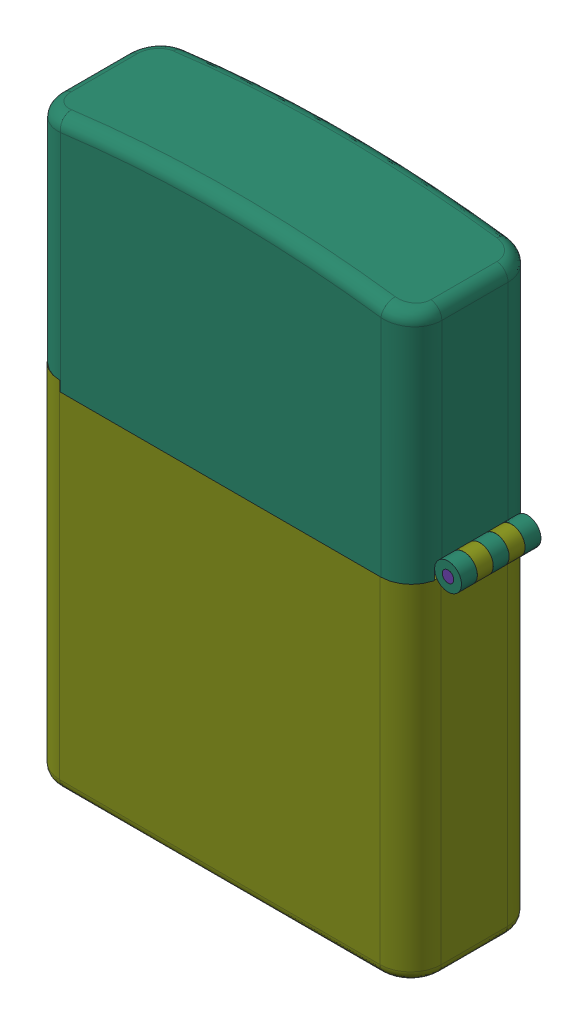
SolidWorks assembly ZLASSEMBLY, configuration Default. Lengths in mm.
Overall size (44.09 59.33 43.46).
18 component instances, 17 part files, 26 mates.
Components (placement in the parent):
- ZLSAP-101 INNER BODY  final-1: ZLSAP-101 INNER BODY  final [Default] at (-7.9372 -6.5366 -12.4236) size (36.03 50.8 10.92)
- ZLSAP- 103 FLINT WHEEL RIVET-1: ZLSAP- 103 FLINT WHEEL RIVET [Default] at (-2.0952 35.9322 -20.3738) x (0.999904 -0.013836 0) z (0 0 1) size (3.05 3.05 5.61)
- ZLSAP-102 FLINT WHEEL-1: ZLSAP-102 FLINT WHEEL [Default] at (-2.0952 35.9322 -19.6118) x (0.056047 -0.998428 0) z (0 0 1) size (10.96 10.96 3.56)
- ZLSAP-104 CAM SPRING-2: ZLSAP-104 CAM SPRING [Default] at (6.0886 28.617 -17.8658) x (0.999917 0 0.012886) z (0.012886 0 -0.999917) size (18.35 4.12 6.22)
- ZLSAP-108 EYELET-1: ZLSAP-108 EYELET [Default] at (9.5562 26.2294 -17.8846) x (-0.386007 0 0.922496) z (0 1 0) size (4.57 4.57 2.79)
- ZLSAP-107 WICK-1: ZLSAP-107 WICK [Default] at (9.5562 32.8921 -17.8846) x (-0.99856 0 0.053653) z (0 -1 0) size (1.28 1.29 20.32)
- ZLSAP-105 CAM-1: ZLSAP-105 CAM [Default] at (23.9735 39.612 -16.7416) x (-0.956559 -0.291538 0) z (0 0 -1) size (10.34 13.18 2.54)
- ZLSAP-106 CAM RIVET PIN-1: ZLSAP-106 CAM RIVET PIN [Default] at (23.7253 34.2136 -20.6278) x (-0.237452 -0.971399 0) z (0 0 1) size (2.79 2.79 5.87)
- SA2-1: SA2 [Default] at (2.1781 20.7012 -47.3424) x (0.77642 0 -0.630216) z (0 1 0) size (32.9 29.26 133.24)
  - ZLSAP-205 SPRING-2: ZLSAP-205 SPRING [COMPRESSED] at (-23.8276 -18.5998 -22.0561) size (3.08 2.67 25.15)
  - ZLSAP-206 SCREW-2: ZLSAP-206 SCREW [Default] at (-23.8276 -18.5998 -29.3713) x (-0.090818 0.995868 0) z (0 0 -1) size (6.35 6.35 9.65)
  - ZLSAP-204 SPRING TIP-2: ZLSAP-204 SPRING TIP [Default] at (-23.8815 -18.7291 7.1666) x (-0.123666 -0.992324 0) z (0.992324 -0.123666 0) size (2.34 7.24 2.34)
  - ZLSAP-203 FLINT-2: ZLSAP-203 FLINT [Default] at (-23.8815 -18.7291 7.1666) x (-0.578855 0.81543 0) z (0 0 1) size (2.29 2.29 2.96)
  - ZLSAP-202 FELT PAD-2: ZLSAP-202 FELT PAD [Default] at (3.6679 -34.702 -27.7965) x (-0.77642 0.630216 0) z (0.630216 0.77642 0) size (34.54 5.27 9.65)
  - ZLSAP-201 TUBE-2: ZLSAP-201 TUBE [Default] at (-23.8276 -18.5998 7.7635) size (4.83 5 35.56)
- ZLSAP-301 LID-2: ZLSAP-301 LID [Default] at (28.9173 24.807 -11.5283) x (-1 0 0) z (0 0 -1) size (40.72 25.09 12.7)
- ZLSAP-302 BODY CASE-2: ZLSAP-302 BODY CASE [Default] at (28.842 -9.7624 -17.8846) x (-1 0 0) z (0 0 -1) size (40.79 36.93 12.7)
- ZLSAP-303 CASE HINGE PIN-2: ZLSAP-303 CASE HINGE PIN [Default] at (30.1882 25.823 -21.8661) x (-0.339081 0.940757 0) z (0 0 1) size (1.14 1.14 7.95)
Mates (geometry in assembly coordinates):
- Concentric8: concentric anti-aligned: circle of ZLSAP-101 INNER BODY  final-1; circle of ZLSAP-104 CAM SPRING-2
- Concentric9: concentric anti-aligned: circle of ZLSAP-101 INNER BODY  final-1; circle of ZLSAP-104 CAM SPRING-2
- Coincident7: coincident anti-aligned: plane of ZLSAP-101 INNER BODY  final-1 through (23.3397 28.4646 -17.8846) normal (0 1 0); plane of ZLSAP-104 CAM SPRING-2 through (6.1287 28.4646 -20.977) normal (0 -1 0)
- Concentric10: concentric anti-aligned: circle of ZLSAP-104 CAM SPRING-2; circle of ZLSAP-108 EYELET-1
- Coincident9: coincident anti-aligned: plane of ZLSAP-104 CAM SPRING-2 through (6.1287 28.7694 -20.977) normal (0 1 0); plane of ZLSAP-108 EYELET-1 through (9.5562 28.7694 -17.8846) normal (0 -1 0)
- Concentric11: concentric aligned: cylinder of ZLSAP-108 EYELET-1 through (9.5562 29.0234 -17.8846) axis (0 -1 0) radius 1.2446; circle of ZLSAP-107 WICK-1
- Concentric14: concentric anti-aligned: cylinder of ZLSAP-101 INNER BODY  final-1 through (-2.0952 35.9322 -25.5808) axis (0 0 1) radius 1.4732; cylinder of ZLSAP- 103 FLINT WHEEL RIVET-1 through (-2.0952 35.9322 -15.4208) axis (0 0 -1) radius 1.0795
- Coincident12: coincident anti-aligned: plane of ZLSAP-101 INNER BODY  final-1 through (-7.9372 44.2634 -15.4208) normal (0 0 1); plane of ZLSAP- 103 FLINT WHEEL RIVET-1 through (-2.0952 35.9322 -15.4208) normal (0 0 -1)
- Width1: width anti-aligned: plane of ZLSAP-105 CAM-1 through (27.0462 40.3092 -16.7416) normal (0 0 1); plane of ZLSAP-105 CAM-1 through (27.0462 40.3092 -19.2816) normal (0 0 -1); plane of ZLSAP-106 CAM RIVET PIN-1 through (23.7253 34.2136 -20.6786) normal (0 0 -1); plane of ZLSAP-106 CAM RIVET PIN-1 through (23.7253 34.2136 -15.3446) normal (0 0 -1)
- Concentric21: concentric aligned: cylinder of ZLSAP-105 CAM-1 through (23.7253 34.2136 -19.2816) axis (0 0 -1) radius 0.9652; cylinder of ZLSAP-106 CAM RIVET PIN-1 through (23.7253 34.2136 -15.3446) axis (0 0 -1) radius 0.9652
- Concentric22: concentric anti-aligned: cylinder of ZLSAP-101 INNER BODY  final-1 through (23.7253 34.2136 -23.3456) axis (0 0 1) radius 0.9779; cylinder of ZLSAP-106 CAM RIVET PIN-1 through (23.7253 34.2136 -15.3446) axis (0 0 -1) radius 0.9652
- Coincident17: coincident anti-aligned: plane of ZLSAP-101 INNER BODY  final-1 through (20.5443 37.0467 -15.3446) normal (0 0 1); plane of ZLSAP-106 CAM RIVET PIN-1 through (23.7253 34.2136 -15.3446) normal (0 0 -1)
- Concentric24: concentric anti-aligned: cylinder of ZLSAP- 103 FLINT WHEEL RIVET-1 through (-2.0952 35.9322 -15.4208) axis (0 0 -1) radius 1.0795; circle of ZLSAP-102 FLINT WHEEL-1
- Width2: width aligned: plane of ZLSAP-102 FLINT WHEEL-1 through (-2.0952 35.9322 -16.1574) normal (0 0 1); plane of ZLSAP-102 FLINT WHEEL-1 through (-2.0952 35.9322 -19.6118) normal (0 0 -1); plane of ZLSAP-101 INNER BODY  final-1 through (3.4928 -6.5366 -19.8404) normal (0 0 1); plane of ZLSAP-101 INNER BODY  final-1 through (3.4928 -6.5366 -15.9288) normal (0 0 -1)
- Width3: width anti-aligned: plane of SA2-1/ZLSAP-202 FELT PAD-2 through (26.8957 -1.8249 -13.0586) normal (0 0 1); plane of SA2-1/ZLSAP-202 FELT PAD-2 through (26.8957 -1.8249 -22.7106) normal (0 0 -1); plane of ZLSAP-101 INNER BODY  final-1 through (27.6228 28.4646 -12.9062) normal (0 0 -1); plane of ZLSAP-101 INNER BODY  final-1 through (-7.9372 28.4646 -22.863) normal (0 0 1)
- Concentric32: concentric aligned: circle of ZLSAP-101 INNER BODY  final-1; cylinder of SA2-1/ZLSAP-201 TUBE-2 through (-4.6003 -7.0954 -17.8846) axis (0 1 0) radius 2.0193
- Coincident45: coincident aligned: plane of ZLSAP-101 INNER BODY  final-1 through (23.3397 28.4646 -17.8846) normal (0 1 0); plane of SA2-1/ZLSAP-201 TUBE-2 through (-4.6003 28.4646 -17.8846) normal (0 1 0)
- Width4: width aligned: plane of ZLSAP-101 INNER BODY  final-1 through (27.6228 28.4646 -12.4236) normal (0 0 1); plane of ZLSAP-101 INNER BODY  final-1 through (-7.9372 28.4646 -23.3456) normal (0 0 -1); plane of ZLSAP-302 BODY CASE-2 through (28.842 -8.6702 -23.7774) normal (0 0 1); plane of ZLSAP-302 BODY CASE-2 through (28.842 -8.6702 -11.9918) normal (0 0 -1)
- Coincident47: coincident anti-aligned: plane of SA2-1/ZLSAP-206 SCREW-2 through (-4.6003 -8.6702 -17.8846) normal (0 -1 0); plane of ZLSAP-302 BODY CASE-2 through (28.842 -8.6702 -17.8846) normal (0 1 0)
- Coincident51: coincident anti-aligned: plane of SA2-1/ZLSAP-206 SCREW-2 through (-4.6003 -8.6702 -17.8846) normal (0 -1 0); plane of ZLSAP-302 BODY CASE-2 through (28.842 -8.6702 -17.8846) normal (0 1 0)
- Distance1: distance = 0.762 mm anti-aligned: plane of ZLSAP-101 INNER BODY  final-1 through (27.6228 28.4646 -23.3456) normal (1 0 0); plane of ZLSAP-302 BODY CASE-2 through (28.3848 -8.6702 -17.8846) normal (-1 0 0)
- Concentric35: concentric aligned: circle of ZLSAP-301 LID-2; cylinder of ZLSAP-302 BODY CASE-2 through (30.1882 25.823 -17.0909) axis (0 0 1) radius 0.5715
- Coincident52: coincident anti-aligned: plane of ZLSAP-301 LID-2 through (28.842 25.823 -15.5034) normal (0 0 -1); plane of ZLSAP-302 BODY CASE-2 through (28.3848 24.7816 -15.5034) normal (0 0 1)
- Concentric36: concentric anti-aligned: cylinder of ZLSAP-301 LID-2 through (30.1882 25.823 -24.2283) axis (0 0 1) radius 0.5715; cylinder of ZLSAP-303 CASE HINGE PIN-2 through (30.1882 25.823 -13.9159) axis (0 0 -1) radius 0.5715
- Coincident55: coincident aligned: plane of ZLSAP-301 LID-2 through (28.842 25.823 -13.9159) normal (0 0 1); plane of ZLSAP-303 CASE HINGE PIN-2 through (30.1882 25.823 -13.9159) normal (0 0 1)
- LimitAngle1: limit planar angle = 0 rad anti-aligned: plane of ZLSAP-301 LID-2 through (28.9173 24.807 -24.2283) normal (0 -1 0); plane of ZLSAP-302 BODY CASE-2 through (28.842 25.7976 -24.2346) normal (0 1 0)
